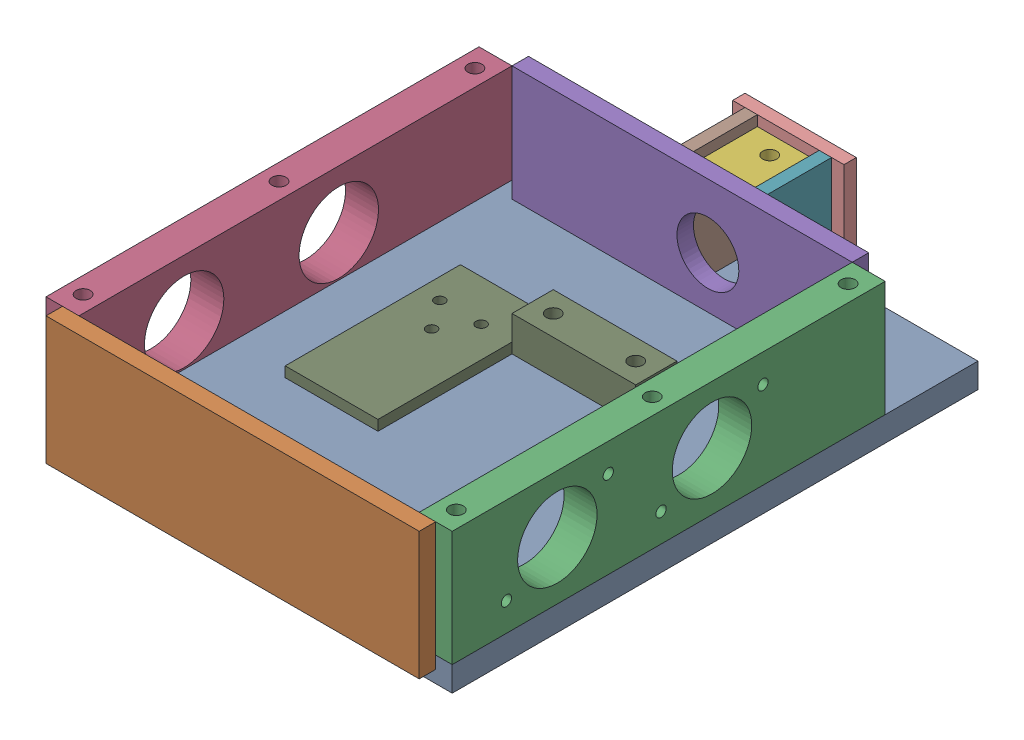
SolidWorks assembly g1_3_1_1_8_1_af0, configuration 默认. Lengths in mm.
Overall size (197 68 263).
11 component instances, 10 part files, 0 mates.
Components (placement in the parent):
- g1_3_1_1_8_1-3_af1-1: g1_3_1_1_8_1-3_af1 [默认] at origin size (197 12 255)
- g1_3_1_1_8_1-1-1: g1_3_1_1_8_1-1 [默认] at (0 37 127.5) x (1 0 0) z (0 -1 0) size (181 8 62)
- g1_3_1_1_8_1-2_af1-1: g1_3_1_1_8_1-2_af1 [默认] at (98.5 40 22.5) x (0 1 0) z (0 0 1) size (56 16 210)
- g1_3_1_1_8_1-2_af0-1: g1_3_1_1_8_1-2_af0 [默认] at (-98.5 40 22.5) x (0 1 0) z (0 0 -1) size (56 16 210)
- g1_3_1_1_8_1-5-1: g1_3_1_1_8_1-5 [默认] at (0 40 -82.5) x (1 0 0) z (0 1 0) size (165 8 56)
- g1_3_1_1_8_1-7_af0-1: g1_3_1_1_8_1-7_af0 [默认] at (12.5 57 -106) size (30 6 31)
- g1_3_1_1_8_1-6-1: g1_3_1_1_8_1-6 [默认] at (27.5 40 -106) x (0 1 0) z (0 0 -1) size (56 6 31)
- g1_3_1_1_8_1-6-2: g1_3_1_1_8_1-6 [默认] at (-8.5 40 -106) x (0 1 0) z (0 0 -1) size (56 6 31)
- g1_3_1_1_8_1-4_af1-1: g1_3_1_1_8_1-4_af1 [默认] at (-10 12 5) size (105 17 85)
- g1_3_1_1_8_1-8_af0-1: g1_3_1_1_8_1-8_af0 [默认] at (12.5 40 -127.5) x (0 1 0) z (1 0 0) size (56 6 54)
- g1_3_1_1_8_1_af0_more-1: g1_3_1_1_8_1_af0_more [默认] at origin size (197 61 238)
